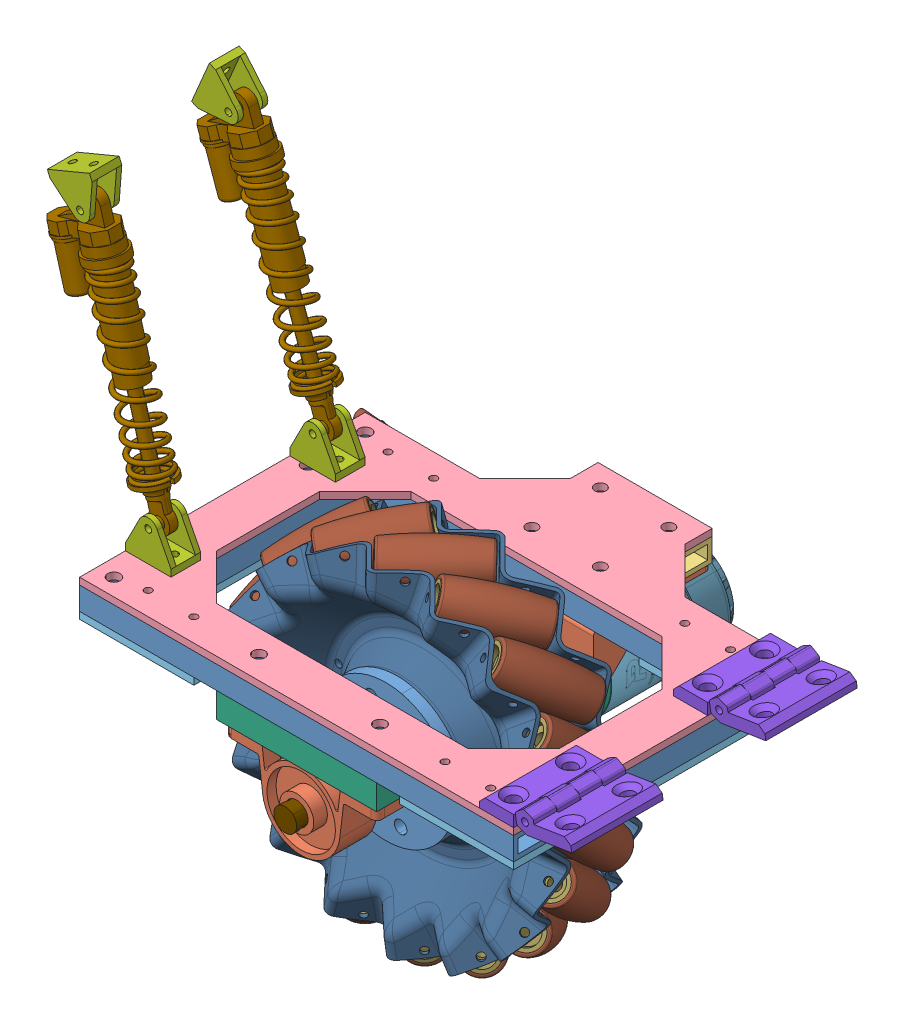
SolidWorks assembly suspension-R, configuration 默认. Lengths in mm.
Overall size (264.55 284.01 183.1).
105 component instances, 30 part files, 56 mates.
Components (placement in the parent):
- Al_Structure-1: Al_Structure [默认] at (-46.393 -16.6731 0) size (190 10 125)
- 3508_10电机座-1: 3508_10电机座 [Default] at (24.7457 -16.6731 39.834) x (-1 0 0) z (0 0 1) size (50 52 52)
- M3508直流无刷减速电机-1: M3508直流无刷减速电机 [默认] at (-63.9604 -40.3546 -130.941) x (-0.381788 -0.92425 0) z (0 0 1) size (70.45 147.45 98.4)
  - M3508直流无刷减速电机.STEP-1: M3508直流无刷减速电机.STEP [Default] at origin size (81.79 158.79 98.4)
    - 2.STEP-1: 2.STEP [Default] at (-1.7887 18.2683 50.441) x (-0.381788 0.92425 0) z (0.92425 0.381788 0) size (59.4 63.3 59.4)
      - 26.STEP-1: 26.STEP [Default] at (0 27 0) x (-0.381788 0 0.92425) z (-0.92425 0 -0.381788) size (22 6 22)
        - 27.STEP-1: 27.STEP [默认] at origin size (22 6 22)
        - 28.STEP-1: 28.STEP [默认] at (0 2.5 0) size (20 0.2 20)
        - 28.STEP-2: 28.STEP [默认] at (0 -2.7 0) size (20 0.2 20)
      - 26.STEP-2: 26.STEP [Default] at (0 34.5 0) x (-0.381788 0 0.92425) z (-0.92425 0 -0.381788) size (22 6 22)
        - 27.STEP-1: 27.STEP [默认] at origin size (22 6 22)
        - 28.STEP-1: 28.STEP [默认] at (0 2.5 0) size (20 0.2 20)
        - 28.STEP-2: 28.STEP [默认] at (0 -2.7 0) size (20 0.2 20)
      - 23.STEP-1: 23.STEP [默认] at origin size (42.01 26 42)
      - 16.STEP-1: 16.STEP [默认] at (0 31 0) x (-0.707107 0 0.707107) z (0 1 0) size (42 42 14)
      - 25.STEP-1: 25.STEP [默认] at (0 38.5 0) x (0 0 1) z (-1 0 0) size (16.7 1 13.43)
      - 17.STEP-1: 17.STEP [默认] at (0 19.3 0) x (-1 0 0) z (0 0 -1) size (26 44 26)
      - 24.STEP-1: 24.STEP [默认] at (0 37.71 0) x (0 1 0) z (0.381788 0 -0.92425) size (0.42 16 16)
      - 18.STEP-1: 18.STEP [默认] at (12.3744 22 12.3744) x (-0.381788 0 0.92425) z (-0.92425 0 -0.381788) size (5.5 12 5.5)
      - 18.STEP-2: 18.STEP [默认] at (12.3744 22 -12.3744) x (0.92425 0 0.381788) z (-0.381788 0 0.92425) size (5.5 12 5.5)
      - 18.STEP-3: 18.STEP [默认] at (-12.3744 22 -12.3744) x (0.381788 0 -0.92425) z (0.92425 0 0.381788) size (5.5 12 5.5)
      - 18.STEP-4: 18.STEP [默认] at (-12.3744 22 12.3744) x (-0.92425 0 -0.381788) z (0.381788 0 -0.92425) size (5.5 12 5.5)
    - 5.STEP-1: 5.STEP [Default] at (56.824 -105.7062 43.091) x (0.954008 0.299781 0) z (-0.299781 0.954008 0) size (12.31 5.48 111.01)
      - 19.STEP-1: 19.STEP [默认] at origin size (12.31 5.48 13.41)
      - 15.STEP-1: 15.STEP [默认] at (-22.7519 0 22.9937) x (-1 0 0) z (0 0 -1) size (2.5 2.5 100)
      - 15.STEP-2: 15.STEP [默认] at (-18.7519 0 22.9937) x (0 1 0) z (0 0 -1) size (2.5 2.5 100)
      - 15.STEP-3: 15.STEP [默认] at (-14.7519 0 22.9937) x (-1 0 0) z (0 0 -1) size (2.5 2.5 100)
      - 20.STEP-1: 20.STEP [默认] at (-1.9783 -5.4851 11.3276) x (1 0 0) z (0 0 -1) size (11.93 4.93 6.5)
    - 1.STEP-1: 1.STEP [默认] at (-1.7887 18.2683 48.441) x (0.923508 -0.383579 0) z (0 0 1) size (42 42 43.4)
    - 4.STEP-1: 4.STEP [默认] at (-1.7887 18.2683 39.841) x (-0.923508 0.383579 0) z (0.383579 0.923508 0) size (13.16 4.25 21.29)
    - 3.STEP-1: 3.STEP [默认] at (4.5067 -1.7659 43.091) x (0.299781 -0.954008 0) z (0.954008 0.299781 0) size (5.77 4 14.5)
- 3510D孔联轴器-1: 3510D孔联轴器 [Default] at (-128.3393 -63.9318 -10.2) x (0.685829 0.727763 0) z (-0.727763 0.685829 0) size (60 27 60)
- 10mm钢制联轴器-1: 10mm钢制联轴器 [默认] at (-49.6804 -47.7533 1.2992) x (0.685829 0.727763 0) z (0 0 1) size (81.96 81.96 49.1)
  - 10mm钢制联轴器.STEP-1: 10mm钢制联轴器.STEP [Default] at origin size (81.96 81.96 49.1)
    - __________.STEP-1: __________.STEP [Default] at (3.7664 -0.9677 32.1012) size (24 24 44.1)
    - 3510______ ____2.STEP-1: 3510______ ____2.STEP [Default] at (9.8274 82.7684 22.1012) x (0.5 -0.866025 0) z (0.866025 0.5 0) size (60 5 60)
- 轴承座-1: 轴承座 [默认] at (-47.6247 -31.9408 44.5) x (-1 0 0) z (0 0 1) size (67 35 18)
- 电机座垫铝管-1: 电机座垫铝管 [Default] at (24.7457 -16.6731 39.834) x (1 0 0) z (0 1 0) size (50 20 10)
- 玻纤上板-1: 玻纤上板 [Default] at (-46.393 -6.6731 0) x (1 0 0) z (0 1 0) size (190 157 3)
- 玻纤下板-1: 玻纤下板 [Default] at (-46.393 -16.6731 0) x (-1 0 0) z (0 -1 0) size (50 125 3)
- 玻纤下板-2: 玻纤下板 [Default] at (-46.393 -16.6731 0) x (1 0 0) z (0 -1 0) size (50 125 3)
- 3DPrinting垫片-1: 3DPrinting垫片 [Default] at (-46.393 -16.6731 0) x (-1 0 0) z (0 -1 0) size (70 20 11)
- 3mm固定座-1: 3mm固定座 [Default] at (-166.7361 -3.6731 11.7194) size (20 17.54 13)
- 3mm固定座-2: 3mm固定座 [Default] at (-166.7361 -3.6731 83.7194) size (20 17.54 13)
- 铰链-1: 铰链 [默认] at (42.216 2.468 -82.5) x (-1 0 0) z (0 0 1) size (40.48 12.73 40)
  - 铰链-1: 铰链 [默认] at (-11.391 1.5222 20) size (24 9.08 40)
  - 铰链-2: 铰链 [默认] at (-11.391 1.5222 60) x (-0.987641 -0.156733 0) z (0 0 -1) size (24 9.08 40)
- 铰链-2: 铰链 [默认] at (42.216 2.468 2.5) x (-1 0 0) z (0 0 1) size (40.48 12.73 40)
  - 铰链-1: 铰链 [默认] at (-11.391 1.5222 20) size (24 9.08 40)
  - 铰链-2: 铰链 [默认] at (-11.391 1.5222 60) x (-0.987641 -0.156733 0) z (0 0 -1) size (24 9.08 40)
- 孔距110mm负压避震器.-1: 孔距110mm负压避震器. [默认] at (-170.847 94.2339 -2.4) x (-0.96253 -0.271174 0) z (0 0 1) size (30.38 119.45 17)
- 孔距110mm负压避震器.-2: 孔距110mm负压避震器. [默认] at (-176.4374 91.3946 -74.4) x (-0.942156 -0.335174 0) z (0 0 1) size (30.38 119.45 17)
- 3mm固定座-3: 3mm固定座 [Default] at (-133.7096 141.372 83.7194) x (-0.923129 -0.38449 0) z (0 0 1) size (20 17.54 13)
- 3mm固定座-4: 3mm固定座 [Default] at (-166.7199 150.9953 11.7194) x (-0.390129 -0.92076 0) z (0 0 1) size (20 17.54 13)
- 麦轮组装左-1: 麦轮组装左 [默认] at (-29.0896 -59.734 -126.7518) x (0.945939 -0.324344 0) z (0 0 1) size (168 168 48.1)
  - 麦轮钣金-1: 麦轮钣金 [默认] at (-20.9276 7.6858 132.4522) size (142.88 142.88 24.05)
  - 麦轮钣金-2: 麦轮钣金 [默认] at (-20.9276 7.6858 129.2518) x (-0.980785 -0.19509 0) z (0 0 -1) size (142.88 142.88 24.05)
  - 滚花橡胶轮组装-1: 滚花橡胶轮组装 [默认] at (60.4121 -1.9858 154.8754) x (0.932849 -0.320965 -0.163627) z (-0.338043 -0.622763 -0.705615) size (18.5 18.5 38)
    - 滚花橡胶轮外-1: 滚花橡胶轮外 [默认] at (-9.896 1.7835 38.5971) size (18.5 18.5 38)
    - 滚花铝柱-1: 滚花铝柱 [默认] at (-9.896 1.7835 38) x (0.787441 0.61639 0) z (-0.61639 0.787441 0) size (13 38 13)
  - 滚花橡胶轮组装-2: 滚花橡胶轮组装 [默认] at (57.9216 29.8777 154.8754) x (0.984668 0.060453 -0.163627) z (-0.073989 -0.704722 -0.705615) size (18.5 18.5 38)
    - 滚花橡胶轮外-1: 滚花橡胶轮外 [默认] at (-9.896 1.7835 38.5971) size (18.5 18.5 38)
    - 滚花铝柱-1: 滚花铝柱 [默认] at (-9.896 1.7835 38) x (0.787441 0.61639 0) z (-0.61639 0.787441 0) size (13 38 13)
  - 滚花橡胶轮组装-3: 滚花橡胶轮组装 [默认] at (43.4271 58.3628 154.8754) x (0.88658 0.432668 -0.163627) z (0.201328 -0.679392 -0.705615) size (18.5 18.5 38)
    - 滚花橡胶轮外-1: 滚花橡胶轮外 [默认] at (-9.896 1.7835 38.5971) size (18.5 18.5 38)
    - 滚花铝柱-1: 滚花铝柱 [默认] at (-9.896 1.7835 38) x (0.787441 0.61639 0) z (-0.61639 0.787441 0) size (13 38 13)
  - 滚花橡胶轮组装-4: 滚花橡胶轮组装 [默认] at (19.1352 79.1327 154.8754) x (0.653519 0.739013 -0.163627) z (0.445995 -0.550632 -0.705615) size (18.5 18.5 38)
    - 滚花橡胶轮外-1: 滚花橡胶轮外 [默认] at (-9.896 1.7835 38.5971) size (18.5 18.5 38)
    - 滚花铝柱-1: 滚花铝柱 [默认] at (-9.896 1.7835 38) x (0.787441 0.61639 0) z (-0.61639 0.787441 0) size (13 38 13)
  - 滚花橡胶轮组装-5: 滚花橡胶轮组装 [默认] at (-11.256 89.0255 154.8754) x (0.320965 0.932849 -0.163627) z (0.622763 -0.338043 -0.705615) size (18.5 18.5 38)
    - 滚花橡胶轮外-1: 滚花橡胶轮外 [默认] at (-9.896 1.7835 38.5971) size (18.5 18.5 38)
    - 滚花铝柱-1: 滚花铝柱 [默认] at (-9.896 1.7835 38) x (0.787441 0.61639 0) z (-0.61639 0.787441 0) size (13 38 13)
  - 滚花橡胶轮组装-6: 滚花橡胶轮组装 [默认] at (-43.1195 86.535 154.8754) x (-0.060453 0.984668 -0.163627) z (0.704722 -0.073989 -0.705615) size (18.5 18.5 38)
    - 滚花橡胶轮外-1: 滚花橡胶轮外 [默认] at (-9.896 1.7835 38.5971) size (18.5 18.5 38)
    - 滚花铝柱-1: 滚花铝柱 [默认] at (-9.896 1.7835 38) x (0.787441 0.61639 0) z (-0.61639 0.787441 0) size (13 38 13)
  - 滚花橡胶轮组装-7: 滚花橡胶轮组装 [默认] at (-71.6045 72.0405 154.8754) x (-0.432668 0.88658 -0.163627) z (0.679392 0.201328 -0.705615) size (18.5 18.5 38)
    - 滚花橡胶轮外-1: 滚花橡胶轮外 [默认] at (-9.896 1.7835 38.5971) size (18.5 18.5 38)
    - 滚花铝柱-1: 滚花铝柱 [默认] at (-9.896 1.7835 38) x (0.787441 0.61639 0) z (-0.61639 0.787441 0) size (13 38 13)
  - 滚花橡胶轮组装-8: 滚花橡胶轮组装 [默认] at (-92.3745 47.7486 154.8754) x (-0.739013 0.653519 -0.163627) z (0.550632 0.445995 -0.705615) size (18.5 18.5 38)
    - 滚花橡胶轮外-1: 滚花橡胶轮外 [默认] at (-9.896 1.7835 38.5971) size (18.5 18.5 38)
    - 滚花铝柱-1: 滚花铝柱 [默认] at (-9.896 1.7835 38) x (0.787441 0.61639 0) z (-0.61639 0.787441 0) size (13 38 13)
  - 滚花橡胶轮组装-9: 滚花橡胶轮组装 [默认] at (-102.2673 17.3574 154.8754) x (-0.932849 0.320965 -0.163627) z (0.338043 0.622763 -0.705615) size (18.5 18.5 38)
    - 滚花橡胶轮外-1: 滚花橡胶轮外 [默认] at (-9.896 1.7835 38.5971) size (18.5 18.5 38)
    - 滚花铝柱-1: 滚花铝柱 [默认] at (-9.896 1.7835 38) x (0.787441 0.61639 0) z (-0.61639 0.787441 0) size (13 38 13)
  - 滚花橡胶轮组装-10: 滚花橡胶轮组装 [默认] at (-99.7768 -14.5061 154.8754) x (-0.984668 -0.060453 -0.163627) z (0.073989 0.704722 -0.705615) size (18.5 18.5 38)
    - 滚花橡胶轮外-1: 滚花橡胶轮外 [默认] at (-9.896 1.7835 38.5971) size (18.5 18.5 38)
    - 滚花铝柱-1: 滚花铝柱 [默认] at (-9.896 1.7835 38) x (0.787441 0.61639 0) z (-0.61639 0.787441 0) size (13 38 13)
  - 滚花橡胶轮组装-11: 滚花橡胶轮组装 [默认] at (-85.2823 -42.9912 154.8754) x (-0.88658 -0.432668 -0.163627) z (-0.201328 0.679392 -0.705615) size (18.5 18.5 38)
    - 滚花橡胶轮外-1: 滚花橡胶轮外 [默认] at (-9.896 1.7835 38.5971) size (18.5 18.5 38)
    - 滚花铝柱-1: 滚花铝柱 [默认] at (-9.896 1.7835 38) x (0.787441 0.61639 0) z (-0.61639 0.787441 0) size (13 38 13)
  - 滚花橡胶轮组装-12: 滚花橡胶轮组装 [默认] at (-60.9904 -63.7611 154.8754) x (-0.653519 -0.739013 -0.163627) z (-0.445995 0.550632 -0.705615) size (18.5 18.5 38)
    - 滚花橡胶轮外-1: 滚花橡胶轮外 [默认] at (-9.896 1.7835 38.5971) size (18.5 18.5 38)
    - 滚花铝柱-1: 滚花铝柱 [默认] at (-9.896 1.7835 38) x (0.787441 0.61639 0) z (-0.61639 0.787441 0) size (13 38 13)
  - 滚花橡胶轮组装-13: 滚花橡胶轮组装 [默认] at (-30.5992 -73.6539 154.8754) x (-0.320965 -0.932849 -0.163627) z (-0.622763 0.338043 -0.705615) size (18.5 18.5 38)
    - 滚花橡胶轮外-1: 滚花橡胶轮外 [默认] at (-9.896 1.7835 38.5971) size (18.5 18.5 38)
    - 滚花铝柱-1: 滚花铝柱 [默认] at (-9.896 1.7835 38) x (0.787441 0.61639 0) z (-0.61639 0.787441 0) size (13 38 13)
  - 滚花橡胶轮组装-14: 滚花橡胶轮组装 [默认] at (1.2643 -71.1634 154.8754) x (0.060453 -0.984668 -0.163627) z (-0.704722 0.073989 -0.705615) size (18.5 18.5 38)
    - 滚花橡胶轮外-1: 滚花橡胶轮外 [默认] at (-9.896 1.7835 38.5971) size (18.5 18.5 38)
    - 滚花铝柱-1: 滚花铝柱 [默认] at (-9.896 1.7835 38) x (0.787441 0.61639 0) z (-0.61639 0.787441 0) size (13 38 13)
  - 滚花橡胶轮组装-15: 滚花橡胶轮组装 [默认] at (29.7494 -56.6689 154.8754) x (0.432668 -0.88658 -0.163627) z (-0.679392 -0.201328 -0.705615) size (18.5 18.5 38)
    - 滚花橡胶轮外-1: 滚花橡胶轮外 [默认] at (-9.896 1.7835 38.5971) size (18.5 18.5 38)
    - 滚花铝柱-1: 滚花铝柱 [默认] at (-9.896 1.7835 38) x (0.787441 0.61639 0) z (-0.61639 0.787441 0) size (13 38 13)
  - 滚花橡胶轮组装-16: 滚花橡胶轮组装 [默认] at (50.5193 -32.377 154.8754) x (0.739013 -0.653519 -0.163627) z (-0.550632 -0.445995 -0.705615) size (18.5 18.5 38)
    - 滚花橡胶轮外-1: 滚花橡胶轮外 [默认] at (-9.896 1.7835 38.5971) size (18.5 18.5 38)
    - 滚花铝柱-1: 滚花铝柱 [默认] at (-9.896 1.7835 38) x (0.787441 0.61639 0) z (-0.61639 0.787441 0) size (13 38 13)
Mates (geometry in assembly coordinates):
- Coincident1: coincident: plane of assembly; plane of assembly; plane of 3508_10电机座-1 through (-68.393 -65.6731 -44.5) normal (0 0 -1); plane of M3508直流无刷减速电机-1/M3508直流无刷减速电机.STEP-1/2.STEP-1/16.STEP-1 through (-55.5854 -36.4836 -44.5) normal (0 0 1)
- Concentric1: concentric: cylinder of assembly; cylinder of assembly; cylinder of 3508_10电机座-1 through (-46.393 -45.6759 -42.5) axis (0 0 -1) radius 13; cylinder of M3508直流无刷减速电机-1/M3508直流无刷减速电机.STEP-1/2.STEP-1/16.STEP-1 through (-46.393 -45.6759 -25.3808) axis (0 0 1) radius 13
- Concentric2: concentric: cylinder of assembly; cylinder of assembly; cylinder of 3508_10电机座-1 through (-46.393 -63.1759 -42.5) axis (0 0 -1) radius 2; cylinder of M3508直流无刷减速电机-1/M3508直流无刷减速电机.STEP-1/2.STEP-1/16.STEP-1 through (-46.393 -63.1759 -44.5) axis (0 0 1) radius 1.65
- Coincident2: coincident: plane of assembly; plane of assembly; plane of Al_Structure-1 through (-46.393 -16.6731 0) normal (0 -1 0); plane of 3508_10电机座-1 through (-68.393 -16.6731 -91.5) normal (0 1 0)
- Coincident3: coincident: plane of assembly; plane of assembly; plane of Al_Structure-1 through (-121.393 -6.6731 -42.5) normal (0 0 1); plane of 3508_10电机座-1 through (-68.393 -65.6731 -42.5) normal (0 0 1)
- Width1: width: plane of assembly; plane of assembly; plane of assembly; plane of assembly; plane of 3508_10电机座-1 through (-71.393 -18.6731 -91.5) normal (-1 0 0); plane of 3508_10电机座-1 through (-21.393 -18.6731 -44.5) normal (1 0 0); plane of Al_Structure-1 through (48.607 -6.6731 62.5) normal (1 0 0); plane of Al_Structure-1 through (-141.393 -6.6731 62.5) normal (-1 0 0)
- Concentric3: concentric: cylinder of assembly; cylinder of assembly; cylinder of M3508直流无刷减速电机-1/M3508直流无刷减速电机.STEP-1/2.STEP-1/17.STEP-1 through (-46.393 -45.6759 -17.2) axis (0 0 1) radius 5; cylinder of 3510D孔联轴器-1 through (-46.393 -45.6759 -17.2) axis (0 0 -1) radius 5.05
- Coincident4: coincident: plane of assembly; plane of assembly; plane of M3508直流无刷减速电机-1/M3508直流无刷减速电机.STEP-1/2.STEP-1/17.STEP-1 through (-46.393 -45.6759 -37.2) normal (0 0 1); plane of 3510D孔联轴器-1 through (-46.393 -45.6759 -37.2) normal (0 0 -1)
- Concentric8: concentric: cylinder of assembly; cylinder of assembly; cylinder of 10mm钢制联轴器-1/10mm钢制联轴器.STEP-1/__________.STEP-1 through (-46.393 -45.6759 67.5004) axis (0 0 -1) radius 5; cylinder of 轴承座-1 through (-46.393 -45.6759 60.5) axis (0 0 -1) radius 5
- Parallel1: parallel: plane of assembly; plane of assembly; plane of Al_Structure-1 through (-46.393 -16.6731 0) normal (0 -1 0); plane of 轴承座-1 through (-12.893 -27.6759 60.5) normal (0 1 0)
- Width2: width: plane of assembly; plane of assembly; plane of assembly; plane of assembly; plane of 轴承座-1 through (-46.393 -45.6759 60.5) normal (0 0 1); plane of 轴承座-1 through (-46.393 -45.6759 44.5) normal (0 0 -1); plane of Al_Structure-1 through (-121.393 -6.6731 42.5) normal (0 0 -1); plane of Al_Structure-1 through (-141.393 -6.6731 62.5) normal (0 0 1)
- Inplace1: in place: plane of 3508_10电机座-1 through (-68.393 -16.6731 -91.5) normal (0 1 0); plane of ? through (0 -16.6731 0) normal (0 1 0); moOrthogonalPlaneRef_w of 3508_10电机座-1 through (-68.393 -16.6731 -91.5) normal (0 1 0); plane of ? through (0 -16.6731 0) normal (0 0 -1); plane of 3508_10电机座-1 through (-68.393 -16.6731 -91.5) normal (0 1 0); plane of ? through (0 -16.6731 0) normal (1 0 0); plane of 3508_10电机座-1 through (-68.393 -16.6731 -91.5) normal (0 1 0); unknown of 电机座垫铝管-1
- Coincident9: coincident: plane of assembly; plane of assembly; plane of 3508_10电机座-1; plane of 电机座垫铝管-1
- Coincident10: coincident: plane of assembly; plane of assembly; moOrthogonalPlaneRef_w of 3508_10电机座-1 through (24.7457 -16.6731 39.834) normal (0 0 -1); plane of 电机座垫铝管-1 through (24.7457 -16.6731 39.834) normal (0 0 -1)
- Coincident11: coincident: plane of assembly; plane of assembly; moOrthogonalPlaneRef_w of 3508_10电机座-1 through (24.7457 -16.6731 39.834) normal (-1 0 0); plane of 电机座垫铝管-1 through (24.7457 -16.6731 39.834) normal (1 0 0)
- Inplace2: in place: plane of Al_Structure-1 through (-46.393 -6.6731 0) normal (0 1 0); plane of ? through (0 -6.6731 0) normal (0 1 0); plane of Al_Structure-1 through (-46.393 -6.6731 0) normal (0 1 0); plane of ? through (0 -6.6731 0) normal (0 0 -1); plane of Al_Structure-1 through (-46.393 -6.6731 0) normal (0 1 0); plane of ? through (0 -6.6731 0) normal (1 0 0); plane of Al_Structure-1 through (-46.393 -6.6731 0) normal (0 1 0); unknown of 玻纤上板-1
- Coincident12: coincident: plane of assembly through (-46.393 -6.6731 0) normal (0 1 0); plane of assembly through (-46.393 -6.6731 0) normal (0 1 0); plane of Al_Structure-1; plane of 玻纤上板-1
- Coincident13: coincident: plane of assembly; plane of assembly; moOrthogonalPlaneRef_w of Al_Structure-1 through (-46.393 -6.6731 0) normal (0 0 -1); plane of 玻纤上板-1 through (-46.393 -6.6731 0) normal (0 0 -1)
- Coincident14: coincident: plane of assembly; plane of assembly; moOrthogonalPlaneRef_w of Al_Structure-1 through (-46.393 -6.6731 0) normal (-1 0 0); plane of 玻纤上板-1 through (-46.393 -6.6731 0) normal (1 0 0)
- Inplace3: in place: plane of Al_Structure-1 through (-46.393 -16.6731 0) normal (0 -1 0); plane of ? through (0 -16.6731 0) normal (0 -1 0); plane of Al_Structure-1 through (-46.393 -16.6731 0) normal (0 -1 0); plane of ? through (0 -16.6731 0) normal (0 0 -1); plane of Al_Structure-1 through (-46.393 -16.6731 0) normal (0 -1 0); plane of ? through (0 -16.6731 0) normal (-1 0 0); plane of Al_Structure-1 through (-46.393 -16.6731 0) normal (0 -1 0); unknown of ?
- Coincident15: coincident: plane of assembly; plane of assembly; plane of Al_Structure-1; plane of 玻纤下板-1
- Coincident16: coincident: plane of Al_Structure-1 through (-46.393 -16.6731 0) normal (0 0 -1); plane of ? through (-46.393 -16.6731 0) normal (0 0 -1)
- Coincident17: coincident: plane of Al_Structure-1 through (-46.393 -16.6731 0) normal (1 0 0); plane of ? through (-46.393 -16.6731 0) normal (-1 0 0)
- Coincident18: coincident: plane of assembly; plane of assembly; plane of Al_Structure-1 through (-46.393 -16.6731 0) normal (0 -1 0); plane of 玻纤下板-2 through (-46.393 -16.6731 0) normal (0 1 0)
- Coincident19: coincident: plane of assembly; plane of assembly; plane of Al_Structure-1 through (-141.393 -6.6731 -62.5) normal (0 0 -1); plane of 玻纤下板-2 through (-101.393 -19.6731 -62.5) normal (0 0 -1)
- Coincident20: coincident: plane of assembly; plane of assembly; plane of Al_Structure-1 through (-141.393 -6.6731 62.5) normal (-1 0 0); plane of 玻纤下板-2 through (-141.393 -19.6731 62.5) normal (-1 0 0)
- Inplace4: in place: plane of Al_Structure-1 through (-46.393 -16.6731 0) normal (0 -1 0); plane of ? through (0 -16.6731 0) normal (0 -1 0); plane of Al_Structure-1 through (-46.393 -16.6731 0) normal (0 -1 0); plane of ? through (0 -16.6731 0) normal (0 0 -1); plane of Al_Structure-1 through (-46.393 -16.6731 0) normal (0 -1 0); plane of ? through (0 -16.6731 0) normal (-1 0 0); plane of Al_Structure-1 through (-46.393 -16.6731 0) normal (0 -1 0); unknown of ?
- Coincident21: coincident: plane of assembly; plane of assembly; plane of Al_Structure-1; plane of 3DPrinting垫片-1
- Coincident22: coincident: plane of Al_Structure-1 through (-46.393 -16.6731 0) normal (0 0 -1); plane of ? through (-46.393 -16.6731 0) normal (0 0 -1)
- Coincident23: coincident: plane of Al_Structure-1 through (-46.393 -16.6731 0) normal (1 0 0); plane of ? through (-46.393 -16.6731 0) normal (-1 0 0)
- Coincident24: coincident: plane of assembly; plane of assembly; plane of 玻纤上板-1 through (-46.393 -3.6731 0) normal (0 1 0); plane of 3mm固定座-1 through (-166.7361 -3.6731 11.7194) normal (0 -1 0)
- Distance1: distance = 20 mm: plane of assembly; plane of assembly; plane of 3mm固定座-1 through (-131.393 9.6269 -42.5) normal (0 0 -1); plane of Al_Structure-1 through (-141.393 -6.6731 -62.5) normal (0 0 -1)
- Coincident27: coincident: plane of assembly; plane of assembly; plane of 玻纤上板-1 through (-46.393 -3.6731 0) normal (0 1 0); plane of 3mm固定座-2 through (-166.7361 -3.6731 83.7194) normal (0 -1 0)
- Distance2: distance = 20 mm: plane of 3mm固定座-2 through (-131.393 9.6269 42.5) normal (0 0 1); plane of Al_Structure-1 through (-141.393 -6.6731 62.5) normal (0 0 1)
- Coincident28: coincident: plane of 玻纤上板-1 through (-46.393 -3.6731 0) normal (0 1 0); plane of 铰链-1/铰链-1 through (53.607 -3.6731 -22.5) normal (0 -1 0)
- Coincident31: coincident: plane of 玻纤上板-1 through (-46.393 -3.6731 0) normal (0 1 0); plane of 铰链-2/铰链-1 through (53.607 -3.6731 62.5) normal (0 -1 0)
- Concentric9: concentric: cylinder of 3mm固定座-2 through (-131.393 9.6269 42.5) axis (0 0 -1) radius 1.5; cylinder of 孔距110mm负压避震器.-1 through (-131.393 9.6269 31) axis (0 0 1) radius 1.5
- Width3: width: plane of 3mm固定座-2 through (-131.393 9.6269 42.5) normal (0 0 1); plane of 3mm固定座-2 through (-131.393 9.6269 29.5) normal (0 0 -1); plane of 孔距110mm负压避震器.-1 through (-131.393 9.6269 34.175) normal (0 0 -1); plane of 孔距110mm负压避震器.-1 through (-131.393 9.6269 37.825) normal (0 0 1)
- Concentric10: concentric: cylinder of assembly; cylinder of assembly; cylinder of 3mm固定座-1 through (-131.393 9.6269 -29.5) axis (0 0 -1) radius 1.5; cylinder of 孔距110mm负压避震器.-2 through (-131.393 9.6269 -41) axis (0 0 1) radius 1.5
- Width4: width: plane of 孔距110mm负压避震器.-2 through (-131.393 9.6269 -39.45) normal (0 0 -1); plane of 孔距110mm负压避震器.-2 through (-131.393 9.6269 -32.55) normal (0 0 1); plane of 3mm固定座-1 through (-131.393 9.6269 -29.5) normal (0 0 1); plane of 3mm固定座-1 through (-131.393 9.6269 -42.5) normal (0 0 -1)
- Coincident36: coincident: plane of Al_Structure-1 through (-141.393 -6.6731 62.5) normal (0 0 1); plane of 铰链-2/铰链-1 through (53.607 0.9457 62.5) normal (0 0 1)
- Coincident37: coincident: plane of 玻纤上板-1 through (48.607 -3.6731 62.5) normal (1 0 0); plane of 铰链-2/铰链-1 through (48.607 6.3269 62.5) normal (1 0 0)
- Coincident38: coincident: plane of Al_Structure-1 through (-141.393 -6.6731 -62.5) normal (0 0 -1); plane of 铰链-1/铰链-1 through (53.607 0.9457 -62.5) normal (0 0 -1)
- Coincident39: coincident: plane of 玻纤上板-1 through (48.607 -3.6731 62.5) normal (1 0 0); plane of 铰链-1/铰链-1 through (48.607 6.3269 -22.5) normal (1 0 0)
- Coincident40: coincident: plane of assembly; plane of assembly; plane of 玻纤上板-1 through (-141.393 -3.6731 -62.5) normal (-1 0 0); plane of 3mm固定座-1 through (-141.393 -0.6731 -39.5) normal (-1 0 0)
- Coincident41: coincident: plane of 玻纤上板-1 through (-141.393 -3.6731 -62.5) normal (-1 0 0); plane of 3mm固定座-2 through (-141.393 -0.6731 32.5) normal (-1 0 0)
- Concentric15: concentric: cylinder of 孔距110mm负压避震器.-1 through (-161.2221 115.5053 32.3) axis (0 0 1) radius 1.5; cylinder of 3mm固定座-3 through (-161.2221 115.5053 42.5) axis (0 0 -1) radius 1.5
- Width5: width: plane of 3mm固定座-3 through (-147.6429 132.3188 40.2) normal (0 0 -1); plane of 3mm固定座-3 through (-147.6429 132.3188 31.8) normal (0 0 1); plane of 孔距110mm负压避震器.-1 through (-165.746 114.2308 38.1) normal (0 0 1); plane of 孔距110mm负压避震器.-1 through (-165.746 114.2308 33.9) normal (0 0 -1)
- Concentric16: concentric: cylinder of 孔距110mm负压避震器.-2 through (-168.2622 113.2641 -39.7) axis (0 0 1) radius 1.5; cylinder of 3mm固定座-4 through (-168.2622 113.2641 -42.5) axis (0 0 1) radius 1.5
- Width6: width: plane of 3mm固定座-4 through (-170.3336 134.7769 -31.8) normal (0 0 -1); plane of 3mm固定座-4 through (-170.3336 134.7769 -40.2) normal (0 0 1); plane of 孔距110mm负压避震器.-2 through (-172.6903 111.6888 -33.9) normal (0 0 1); plane of 孔距110mm负压避震器.-2 through (-172.6903 111.6888 -38.1) normal (0 0 -1)
- Coincident42: coincident: plane of assembly; plane of assembly; plane of 3510D孔联轴器-1 through (-46.393 -45.6759 -10.2) normal (0 0 1); plane of 麦轮组装左-1/麦轮钣金-2 through (-46.393 -45.6759 -10.2) normal (0 0 -1)
- Coincident43: coincident: plane of assembly; plane of assembly; plane of 10mm钢制联轴器-1/10mm钢制联轴器.STEP-1/3510______ ____2.STEP-1 through (-46.393 -45.6759 18.4004) normal (0 0 -1); plane of 麦轮组装左-1/麦轮钣金-1 through (-46.393 -45.6759 18.4004) normal (0 0 1)
- Concentric17: concentric: cylinder of 3510D孔联轴器-1 through (-52.8583 -24.1248 -15.2) axis (0 0 1) radius 2.75; cylinder of 麦轮组装左-1/麦轮钣金-2 through (-52.8583 -24.1248 -10.2) axis (0 0 -1) radius 2.6
- Concentric18: concentric: cylinder of 3510D孔联轴器-1 through (-68.2894 -40.4995 -15.2) axis (0 0 1) radius 2.75; cylinder of 麦轮组装左-1/麦轮钣金-2 through (-68.2894 -40.4995 -10.2) axis (0 0 -1) radius 2.6
- Concentric19: concentric: cylinder of assembly; circle of assembly; cylinder of 10mm钢制联轴器-1/10mm钢制联轴器.STEP-1/3510______ ____2.STEP-1 through (-68.2894 -40.4995 18.4004) axis (0 0 1) radius 2.75; circle of 麦轮组装左-1/麦轮钣金-1
- Concentric20: concentric: cylinder of assembly; circle of assembly; cylinder of 10mm钢制联轴器-1/10mm钢制联轴器.STEP-1/3510______ ____2.STEP-1 through (-61.8241 -62.0506 18.4004) axis (0 0 1) radius 2.75; circle of 麦轮组装左-1/麦轮钣金-1
